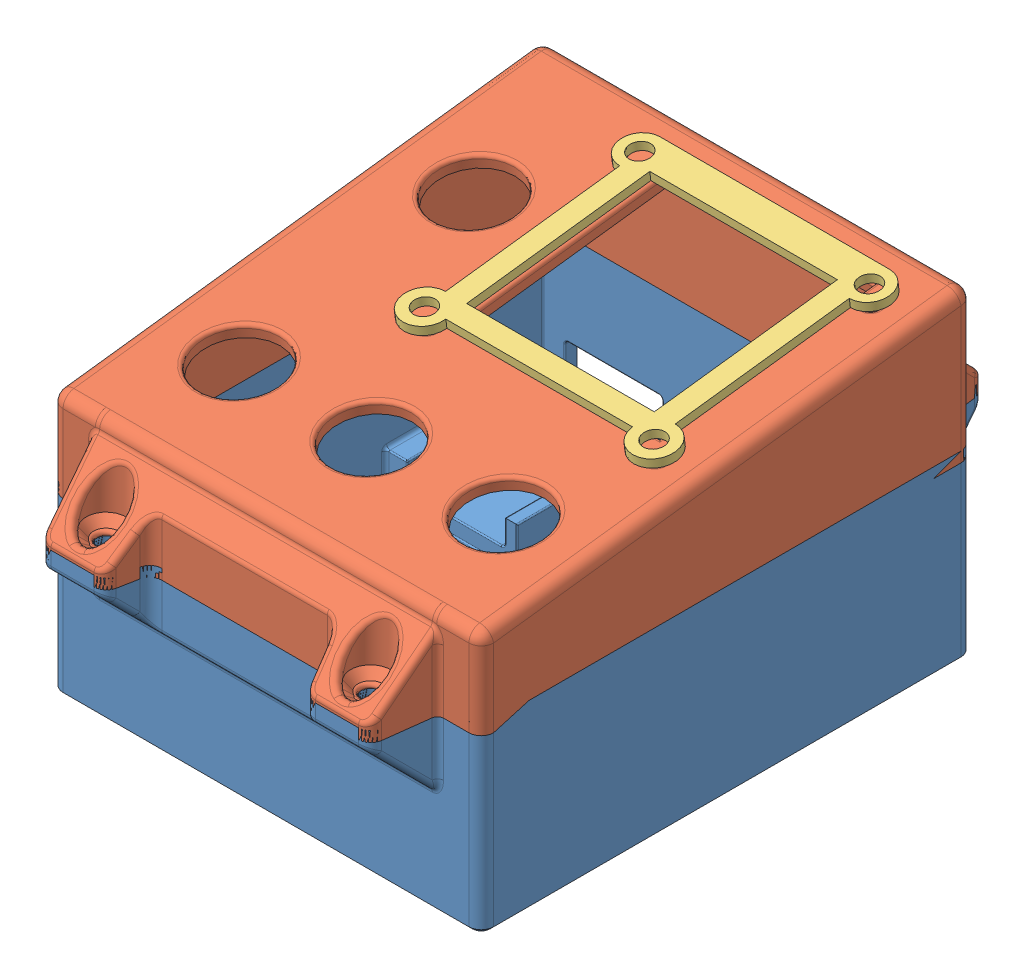
SolidWorks assembly Assem2, configuration Default. Lengths in mm.
Overall size (70 54.5 99.89).
3 component instances, 3 part files, 1 mates.
Components (placement in the parent):
- enclosure_base_v4-1: enclosure_base_v4 [Default] at origin size (70 30 99.89)
- interface_shield_v6-1: interface_shield_v6 [Default] at (0 27.3232 0) size (70 24.73 99.89)
- screen_shield-1: screen_shield [Default] at (0 46.6969 18.2114) x (1 0 0) z (0 -0.124035 0.992278) size (44.32 1.4 42.09)
Mates (geometry in assembly coordinates):
- Concentric1: concentric anti-aligned: circle of enclosure_base_v4-1; circle of interface_shield_v6-1
